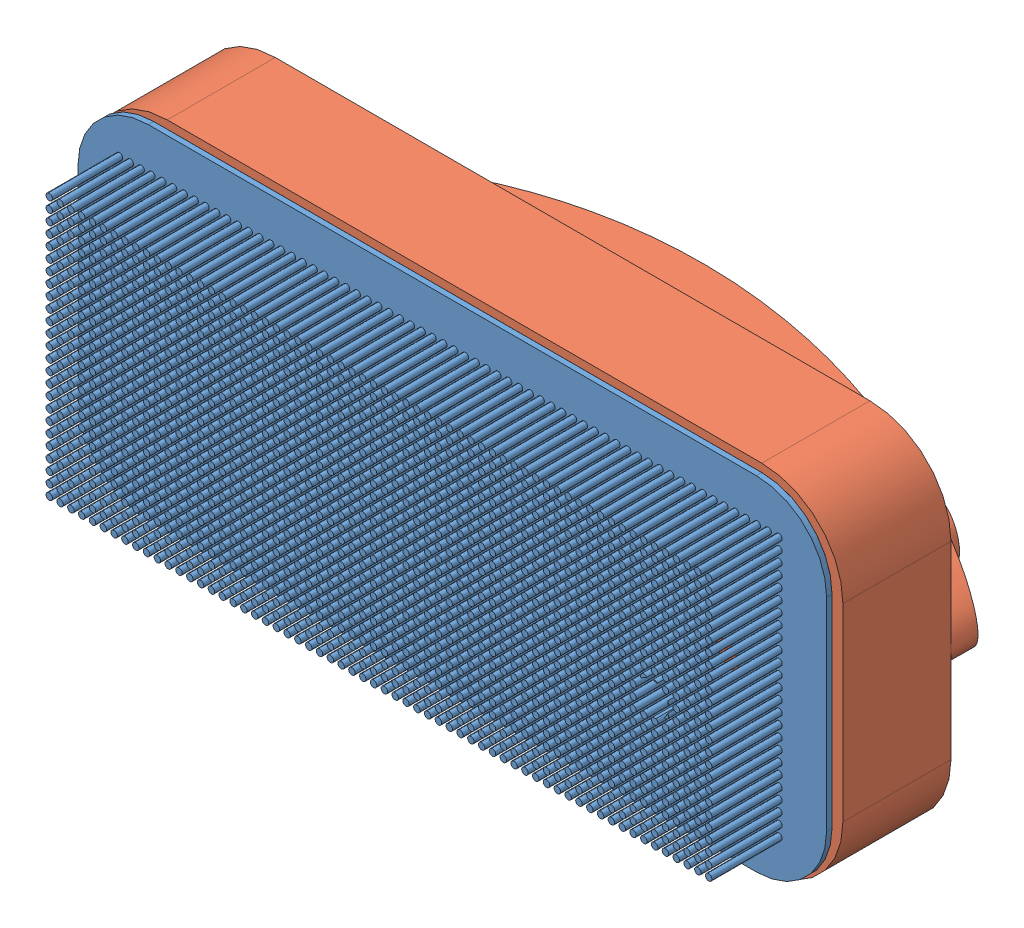
SolidWorks assembly Assem1, configuration Default. Lengths in mm.
Overall size (170.48 65 66.39).
2 component instances, 2 part files, 3 mates.
Components (placement in the parent):
- pdd scrub bottom-1: pdd scrub bottom [Default] at (56.363 58.7358 103.5487) size (138.5 63.5 19)
- pdd scrub top-1: pdd scrub top [Default] at (56.613 58.4858 107.5387) x (-1 0 0) z (0 0 -1) size (170.48 65 51.38)
Mates (geometry in assembly coordinates):
- Coincident1: coincident: plane of pdd scrub bottom-1 through (87.363 88.3858 106.5387) normal (0 0 -1); plane of pdd scrub top-1 through (91.2896 87.9858 106.5387) normal (0 0 1)
- Coincident2: coincident: plane of pdd scrub bottom-1 through (1.113 27.9858 108.5487) normal (0 -1 0); plane of pdd scrub top-1 through (126.613 27.9858 87.5387) normal (0 1 0)
- Coincident3: coincident anti-aligned: plane of pdd scrub bottom-1 through (124.613 40.9858 108.5487) normal (1 0 0); plane of pdd scrub top-1 through (124.613 25.9858 87.5387) normal (-1 0 0)
